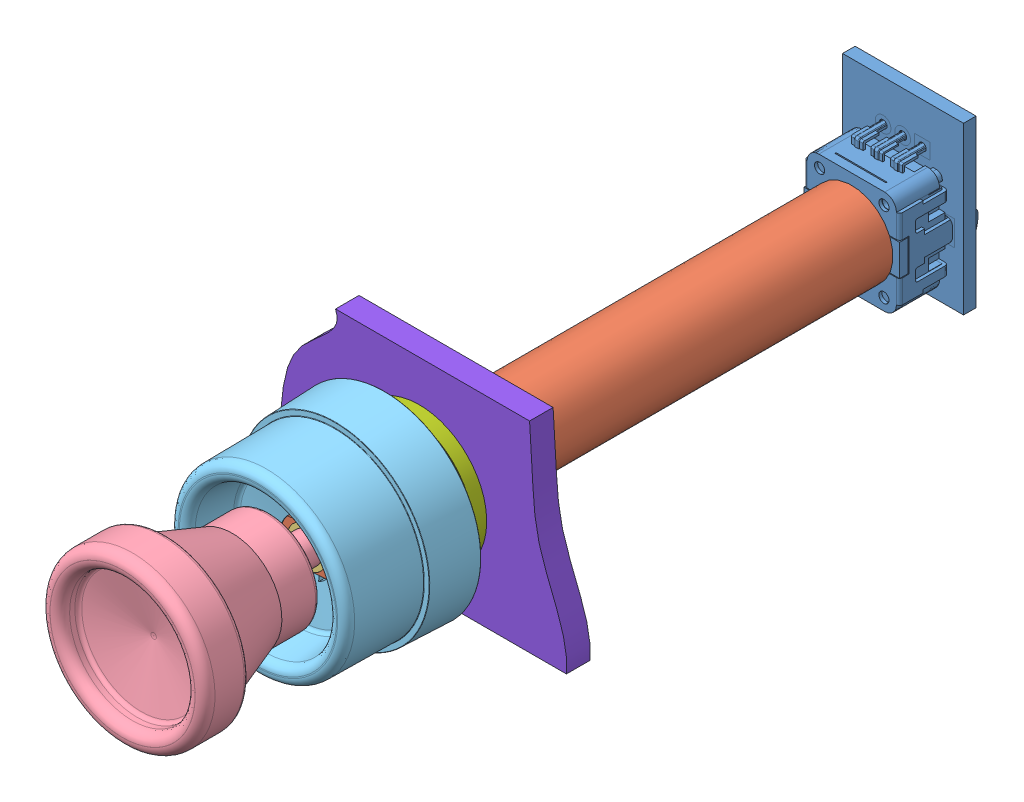
SolidWorks assembly 0100_ASM_rotary_encoder, configuration Domyślna. Lengths in mm.
Overall size (37.1 34.65 103.22).
9 component instances, 8 part files, 19 mates.
Components (placement in the parent):
- 0101_PCB_rotary_encoder-1: 0101_PCB_rotary_encoder [Domyślna] at (14.1302 -4.5986 16.2526) size (15.43 21.18 25.2)
- 0102 Sruba_nosna-1: 0102 Sruba_nosna [Domyślna] at (0.2917 -1.7366 22.8012) x (0.077806 -0.996968 0) z (0 0 1) size (10.5 10.5 69.5)
- 0103 Pokretlo-1: 0103 Pokretlo [Domyślna] at (0.2917 -1.7366 40.6012) x (0 1 0) z (0 0 -1) size (5.8 5.8 59.5)
- 0006 Bezel_pokretlo-1: 0006 Bezel_pokretlo [Domyślna] at (0.2917 -1.7366 115.8202) x (-0.013799 -0.999905 0) z (0 0 1) size (21.05 21.05 32.3)
- 0005 Bezel_fix-2: 0005 Bezel_fix [Domyślna] at (0.2917 -1.7366 82.3766) x (-0.753692 -0.657228 0) z (-0.657228 0.753692 0) size (24.56 16.18 24.56)
- 0105 Naktętka M10x0.75-1: 0105 Naktętka M10x0.75 [Domyślna] at (0.2917 -1.7366 79.7012) x (0.998715 0.050675 0) z (0 0 1) size (15.95 14.46 3.1)
- 0104 Podkładka-1: 0104 Podkładka [Domyślna] at (0.2917 -1.7366 77.9712) size (17.2 17.2 1.73)
- 0007 Mustang_dashboard-2: 0007 Mustang_dashboard [Default] at (73.4945 -19.6234 74.9712) x (1 0 0) z (0 -1 0) size (37.1 3 25.6)
- 0105 Naktętka M10x0.75-2: 0105 Naktętka M10x0.75 [Domyślna] at (0.2917 -1.7366 71.8712) size (15.95 14.46 3.1)
Mates (geometry in assembly coordinates):
- Wspólnie1: coincident anti-aligned: plane of 0101_PCB_rotary_encoder-1 through (0.2917 -1.7366 22.8012) normal (0 0 1); plane of 0102 Sruba_nosna-1 through (0.2917 -1.7366 22.8012) normal (0 0 -1)
- Koncentryczne1: concentric aligned: circle of 0101_PCB_rotary_encoder-1; circle of 0102 Sruba_nosna-1
- Wspólnie2: coincident anti-aligned: plane of 0101_PCB_rotary_encoder-1 through (0.2917 -9.6566 37.8012) normal (0 0 1); plane of 0103 Pokretlo-1 through (0.2917 -1.7366 37.8012) normal (0 0 -1)
- Koncentryczne2: concentric aligned: cylinder of 0102 Sruba_nosna-1 through (0.2917 -1.7366 84.3012) axis (0 0 -1) radius 5.25; cylinder of 0103 Pokretlo-1 through (0.2917 -1.7366 92.3012) axis (0 0 -1) radius 2.5
- Równolegle1: parallel aligned: plane of 0101_PCB_rotary_encoder-1 through (-0.2083 1.2214 37.8012) normal (1 0 0); plane of 0103 Pokretlo-1 through (0.7417 -1.7366 37.8012) normal (1 0 0)
- Koncentryczne3: concentric aligned: cylinder of 0103 Pokretlo-1 through (0.2917 -1.7366 92.3012) axis (0 0 1) radius 1.75; cylinder of 0006 Bezel_pokretlo-1 through (0.2917 -1.7366 83.5202) axis (0 0 1) radius 1.9
- Koncentryczne9: concentric anti-aligned: cylinder of 0102 Sruba_nosna-1 through (0.2917 -1.7366 84.3012) axis (0 0 -1) radius 5.25; cone of 0005 Bezel_fix-2 through (0.2917 -1.7366 86.0861) axis (0 0 1)
- Równolegle3: parallel anti-aligned: plane of 0102 Sruba_nosna-1 through (4.7036 1.0652 74.8773) normal (-0.077806 0.996968 0); plane of 0005 Bezel_fix-2 through (1.2957 0.8211 96.5766) normal (0.077806 -0.996968 0)
- Zablokuj1: lock: unknown of 0101_PCB_rotary_encoder-1; unknown of 0102 Sruba_nosna-1
- Zablokuj2: lock: unknown of 0102 Sruba_nosna-1; unknown of 0005 Bezel_fix-2
- Zablokuj3: lock: unknown of 0102 Sruba_nosna-1; unknown of 0006 Bezel_pokretlo-1
- Koncentryczne10: concentric aligned: circle of 0102 Sruba_nosna-1; circle of 0105 Naktętka M10x0.75-1
- Odległość1: distance = 1.5 mm aligned: plane of 0102 Sruba_nosna-1 through (0.2917 -1.7366 84.3012) normal (0 0 1); plane of 0105 Naktętka M10x0.75-1 through (0.2917 -1.7366 82.8012) normal (0 0 1)
- Koncentryczne12: concentric anti-aligned: cylinder of 0102 Sruba_nosna-1 through (0.2917 -1.7366 84.3012) axis (0 0 -1) radius 5.25; cylinder of 0104 Podkładka-1 through (0.2917 -1.7366 58.728) axis (0 0 1) radius 5.48
- Wspólnie5: coincident anti-aligned: plane of 0105 Naktętka M10x0.75-1 through (0.2917 -1.7366 79.7012) normal (0 0 -1); plane of 0104 Podkładka-1 through (0.2917 -1.7366 79.7012) normal (0 0 1)
- Koncentryczne13: concentric anti-aligned: cylinder of 0102 Sruba_nosna-1 through (0.2917 -1.7366 84.3012) axis (0 0 -1) radius 5.25; cylinder of 0007 Mustang_dashboard-2 through (0.2917 -1.7366 74.9712) axis (0 0 1) radius 5.25
- Wspólnie6: coincident anti-aligned: plane of 0104 Podkładka-1 through (0.2917 -1.7366 77.9712) normal (0 0 -1); plane of 0007 Mustang_dashboard-2 through (36.6542 -1.0497 77.9712) normal (0 0 1)
- Koncentryczne14: concentric anti-aligned: cylinder of 0102 Sruba_nosna-1 through (0.2917 -1.7366 84.3012) axis (0 0 -1) radius 5.25; cylinder of 0105 Naktętka M10x0.75-2 through (0.2917 -1.7366 71.8712) axis (0 0 1) radius 4.594
- Wspólnie7: coincident anti-aligned: plane of 0007 Mustang_dashboard-2 through (36.6542 -1.0497 74.9712) normal (0 0 -1); plane of 0105 Naktętka M10x0.75-2 through (0.2917 -1.7366 74.9712) normal (0 0 1)
